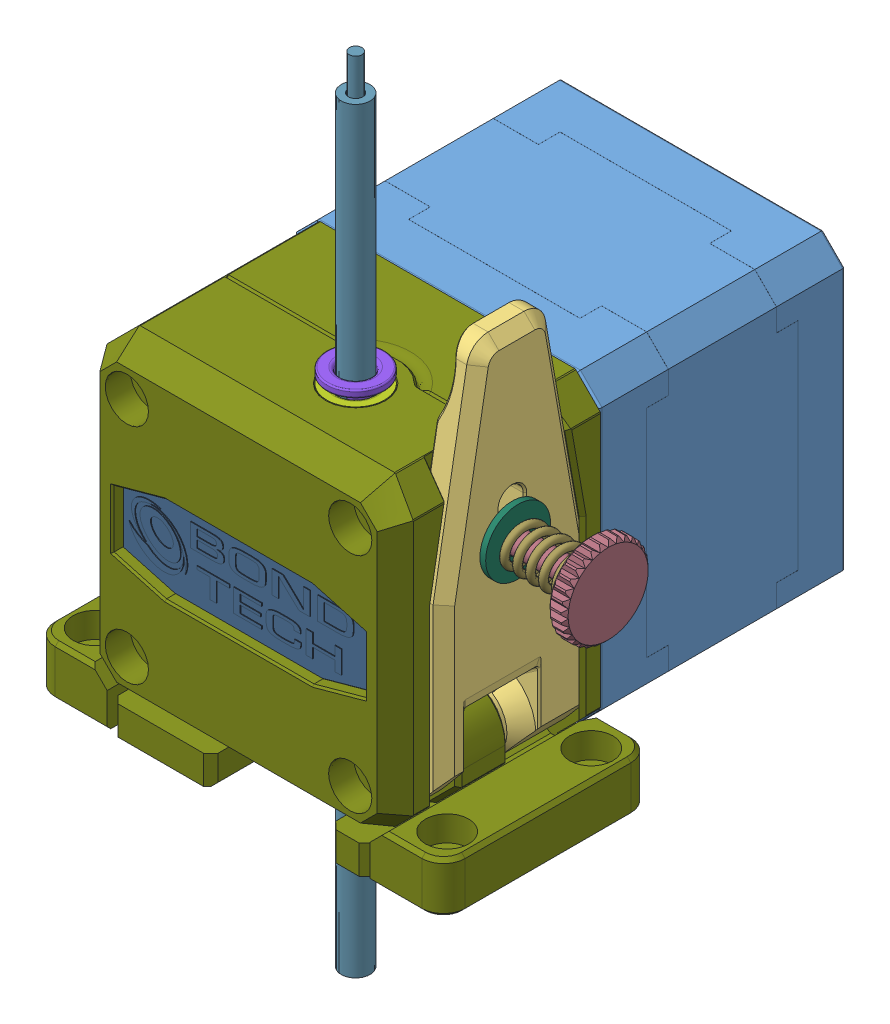
SolidWorks assembly Bondtech Mini, configuration Default. Lengths in mm.
Overall size (64.25 110 63).
20 component instances, 16 part files, 0 mates.
Components (placement in the parent):
- Nema17-42BYGHW811-1: Nema17-42BYGHW811 [Default] at (-22.4798 26.5989 -52.7086) size (42.3 42.3 56)
- Drivewheel_cmpl(Default)-1: Drivewheel_cmpl(Default) [Default] at (-22.4798 26.5989 -8.7086) x (0.998413 -0.056314 0) z (0 0 -1) size (9.55 9.55 14.03)
- Drivewheel_cmpl(Default)-2: Drivewheel_cmpl(Default) [Default] at (-13.9798 26.5989 -8.7086) x (0.330935 0.943654 0) z (0 0 -1) size (9.55 9.55 14.03)
- Hinge(Default)-1: Hinge(Default) [Default] at (-22.4798 26.5989 4.2914) size (17.56 55 20.25)
- K3x5x7-1: K3x5x7 [Default] at (-13.9798 26.5989 -9.2086) x (0.524663 -0.85131 0) z (0 0 1) size (4.8 4.85 7)
- K3x5x7-2: K3x5x7 [Default] at (-13.9798 26.5989 -2.2086) x (0.975095 -0.221789 0) z (0 0 1) size (4.8 4.85 7)
- stift 3-1: stift 3 [Default] at (-13.9798 26.5989 -15.7086) x (-0.4441 -0.895977 0) z (-0.895977 0.4441 0) size (3 20 3)
- socket head cap screw_iso(ISO 4762 M3 x 30 --- 18N)-1: socket head cap screw_iso(ISO 4762 M3 x 30 --- 18N) [Default] at (-6.9798 42.0989 9.7914) x (0 0 -1) z (1 0 0) size (15.73 3 3)
- socket head cap screw_iso(ISO 4762 M3 x 30 --- 18N)-2: socket head cap screw_iso(ISO 4762 M3 x 30 --- 18N) [Default] at (-6.9798 11.0989 9.7914) x (0 0 -1) z (1 0 0) size (15.73 3 3)
- BowdenConnector1(Default)-1: BowdenConnector1(Default) [Default] at (-18.2298 47.8489 -1.7086) x (-0.947381 0 -0.320107) z (0.320107 0 -0.947381) size (8.15 3.95 8.15)
- Bowden2(Default)-1: Bowden2(Default) [Default] at (-18.2298 49.8489 -1.7086) x (0.984821 0 -0.173573) z (0.173573 0 0.984821) size (8 7.01 8)
- Trisert 136-M3-1: Trisert 136-M3 [Default] at (-4.7298 36.5989 -5.2086) x (0 -0.909095 0.416589) z (0 0.416589 0.909095) size (4.3 5.2 4.28)
- Dekal1-1: Dekal1 [Default] at (-23.4798 26.5989 -20.2086) size (34.8 11.8 0.2)
- socket head cap screw_iso(ISO 4762 M3 x 10 --- 10N)-1: socket head cap screw_iso(ISO 4762 M3 x 10 --- 10N) [Default] at (-37.9798 42.0989 -10.7086) x (0 0 -1) z (1 0 0) size (13 5.5 5.5)
- socket head cap screw_iso(ISO 4762 M3 x 10 --- 10N)-2: socket head cap screw_iso(ISO 4762 M3 x 10 --- 10N) [Default] at (-37.9798 11.0989 -10.7086) x (0 0 -1) z (1 0 0) size (13 5.5 5.5)
- Fjäder-1: Fjäder [Default] at (0.8202 36.5989 -5.2086) x (0 -0.070927 -0.997482) z (0 -0.997482 0.070927) size (6.23 11.9 6.23)
- Wiberger-din653_m3_16-1: Wiberger-din653_m3_16 [Default] at (10.8202 36.5989 -5.2086) x (0 0.969282 0.245953) z (0 0.245953 -0.969282) size (12.09 22.5 12.08)
- Bowdentube+filament(Default)-1: Bowdentube+filament(Default) [Default] at (-18.2298 42.792 -1.7086) x (-0.111414 0 -0.993774) z (0.993774 0 -0.111414) size (4 110 4)
- Bricka DIN9021 STÅL 3,2x9x0.8FZB-1: Bricka DIN9021 STÅL 3,2x9x0.8FZB [Default] at (0.8202 36.5989 -5.2086) x (0 -0.692172 0.721733) z (0 -0.721733 -0.692172) size (9 0.8 9)
- HusDirectQR2-1: HusDirectQR2 [Default] at (-22.4798 26.5989 -18.7086) size (56.9 47 29)
